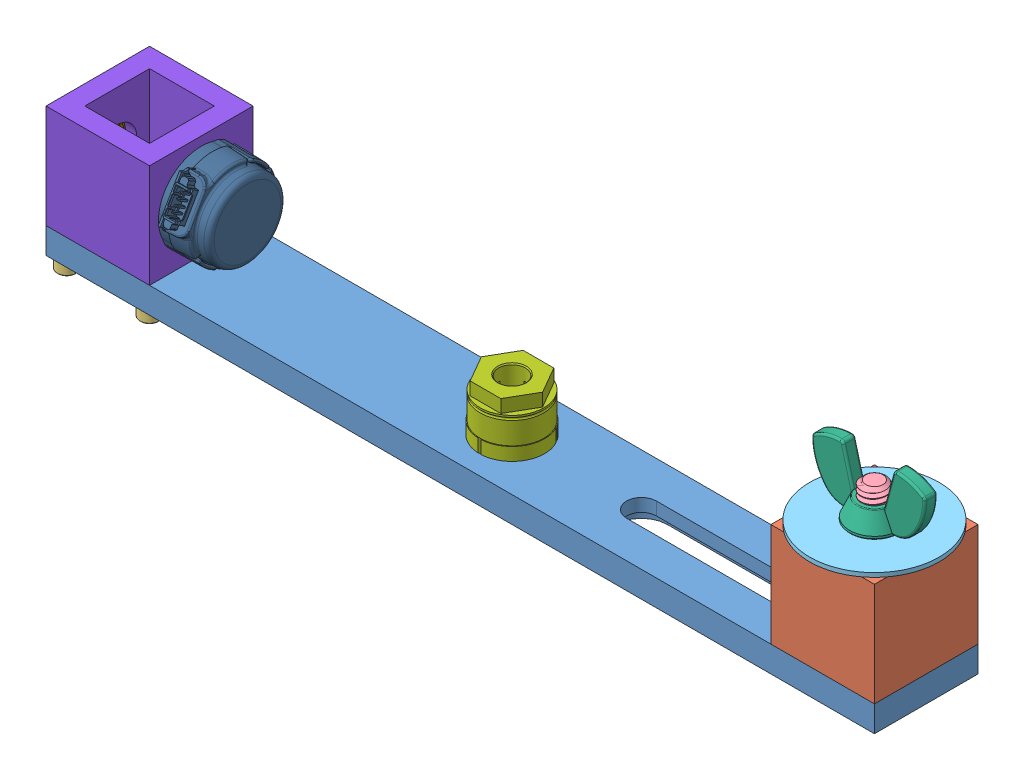
SolidWorks assembly CompleteHorizontalArm, configuration Default. Lengths in mm.
Overall size (207.39 50.04 31.96).
15 component instances, 10 part files, 22 mates.
Components (placement in the parent):
- HorizontalArm-2: HorizontalArm [Default] at (-82.3607 5.9112 59.7963) x (1 0 0) z (0 0 -1) size (203.2 6.35 25.4)
- CounterWeight-1: CounterWeight [Default] at (95.4393 5.9112 85.1963) size (25.4 25.4 25.4)
- 4_40CapScrew-1: 4_40CapScrew [90128A110] at (-79.8207 12.2612 82.6563) x (1 0 0) z (0 1 0) size (4.65 4.65 15.82)
- 4_40CapScrew-4: 4_40CapScrew [90128A110] at (-59.5007 12.2612 62.3363) x (1 0 0) z (0 1 0) size (4.65 4.65 15.82)
- 4_40CapScrew-5: 4_40CapScrew [90128A110] at (-79.8207 12.2612 62.3363) x (1 0 0) z (0 1 0) size (4.65 4.65 15.82)
- 4_40CapScrew-6: 4_40CapScrew [90128A110] at (-59.5007 12.2612 82.6563) x (1 0 0) z (0 1 0) size (4.65 4.65 15.82)
- 1_4x20CapScrew-1: 1_4x20CapScrew [93615A425] at (108.1393 40.8362 72.4963) x (1 0 0) z (0 1 0) size (9.53 9.53 42.04)
- LargeWasher-1: LargeWasher [91525A124] at (108.1393 31.3112 72.4963) x (1 0 0) z (0 -1 0) size (31.75 31.75 1.02)
- WingNut-1: WingNut [93575A029] at (108.1393 32.3272 72.4963) x (1 0 0) z (0 -1 0) size (27.78 12.25 14.47)
- Keyless Bushing_withFeatures-1: Keyless Bushing_withFeatures [Default] at (19.2393 -0.3118 72.4963) x (1 0 0) z (0 -1 0) size (16 16 19.18)
- EncoderBlock-2: EncoderBlock [Default] at (-66.0559 16.3168 69.5231) size (37.74 31.82 30.88)
  - BearingBlock-1: BearingBlock [Default] at (-16.3048 -10.4057 15.6733) size (25.4 25.4 25.4)
  - BallBearing-1: BallBearing [57155K322] at (-15.7333 2.2943 2.9733) x (0 0 -1) z (1 0 0) size (10.72 10.72 3.17)
  - BallBearing-2: BallBearing [57155K322] at (4.9042 2.2943 2.9733) x (0 0 -1) z (1 0 0) size (10.72 10.72 3.17)
  - E4P-X-250-X-S-D-D-X-1: E4P-X-250-X-S-D-D-X [Default] at (9.0952 2.2943 2.9733) x (0 -0.866025 -0.5) z (0 -0.5 0.866025) size (24.23 14.38 21.67)
Mates (geometry in assembly coordinates):
- Coincident4: coincident anti-aligned: plane of HorizontalArm-2 through (-82.3607 5.9112 59.7963) normal (0 1 0); plane of CounterWeight-1 through (95.4393 5.9112 85.1963) normal (0 -1 0)
- Coincident5: coincident anti-aligned: line of HorizontalArm-2 through (120.8393 5.9112 85.1963) axis (-1 0 0); line of CounterWeight-1 through (95.4393 5.9112 85.1963) axis (1 0 0)
- Coincident6: coincident anti-aligned: line of HorizontalArm-2 through (120.8393 5.9112 59.7963) axis (0 0 1); line of CounterWeight-1 through (120.8393 5.9112 85.1963) axis (0 0 -1)
- Concentric4: concentric anti-aligned: circle of HorizontalArm-2; circle of 4_40CapScrew-1
- Coincident7: coincident anti-aligned: plane of HorizontalArm-2 through (-82.3607 -0.4388 59.7963) normal (0 -1 0); plane of 4_40CapScrew-1 through (-79.8207 -0.4388 82.6563) normal (0 1 0)
- Concentric5: concentric anti-aligned: circle of HorizontalArm-2; circle of 4_40CapScrew-4
- Coincident8: coincident anti-aligned: plane of HorizontalArm-2 through (-82.3607 -0.4388 59.7963) normal (0 -1 0); plane of 4_40CapScrew-4 through (-59.5007 -0.4388 62.3363) normal (0 1 0)
- Concentric6: concentric anti-aligned: circle of HorizontalArm-2; circle of 4_40CapScrew-5
- Coincident9: coincident anti-aligned: plane of HorizontalArm-2 through (-82.3607 -0.4388 59.7963) normal (0 -1 0); plane of 4_40CapScrew-5 through (-79.8207 -0.4388 62.3363) normal (0 1 0)
- Concentric7: concentric anti-aligned: circle of HorizontalArm-2; circle of 4_40CapScrew-6
- Coincident10: coincident anti-aligned: plane of HorizontalArm-2 through (-82.3607 -0.4388 59.7963) normal (0 -1 0); plane of 4_40CapScrew-6 through (-59.5007 -0.4388 82.6563) normal (0 1 0)
- Concentric8: concentric aligned: circle of HorizontalArm-2; circle of 1_4x20CapScrew-1
- Coincident11: coincident anti-aligned: plane of HorizontalArm-2 through (108.1393 2.7362 72.4963) normal (0 -1 0); plane of 1_4x20CapScrew-1 through (108.1393 2.7362 72.4963) normal (0 1 0)
- Concentric9: concentric anti-aligned: circle of 1_4x20CapScrew-1; circle of LargeWasher-1
- Coincident12: coincident anti-aligned: plane of CounterWeight-1 through (95.4393 31.3112 85.1963) normal (0 1 0); plane of LargeWasher-1 through (108.1393 31.3112 72.4963) normal (0 -1 0)
- Concentric10: concentric aligned: circle of LargeWasher-1; circle of WingNut-1
- Coincident13: coincident anti-aligned: plane of LargeWasher-1 through (108.1393 32.3272 72.4963) normal (0 1 0); plane of WingNut-1 through (108.1393 32.3272 72.4963) normal (0 -1 0)
- Concentric11: concentric anti-aligned: circle of HorizontalArm-2; circle of Keyless Bushing_withFeatures-1
- Coincident15: coincident aligned: plane of HorizontalArm-2 through (-82.3607 -0.4388 59.7963) normal (0 -1 0); plane of Keyless Bushing_withFeatures-1 through (19.2393 -0.4388 72.4963) normal (0 -1 0)
- Concentric12: concentric: circle of HorizontalArm-2; circle of EncoderBlock-2/BearingBlock-1
- Concentric13: concentric: circle of HorizontalArm-2; circle of EncoderBlock-2/BearingBlock-1
- Coincident16: coincident anti-aligned: plane of HorizontalArm-2 through (-82.3607 5.9112 59.7963) normal (0 1 0); plane of EncoderBlock-2/BearingBlock-1 through (-82.3607 5.9112 85.1963) normal (0 -1 0)
